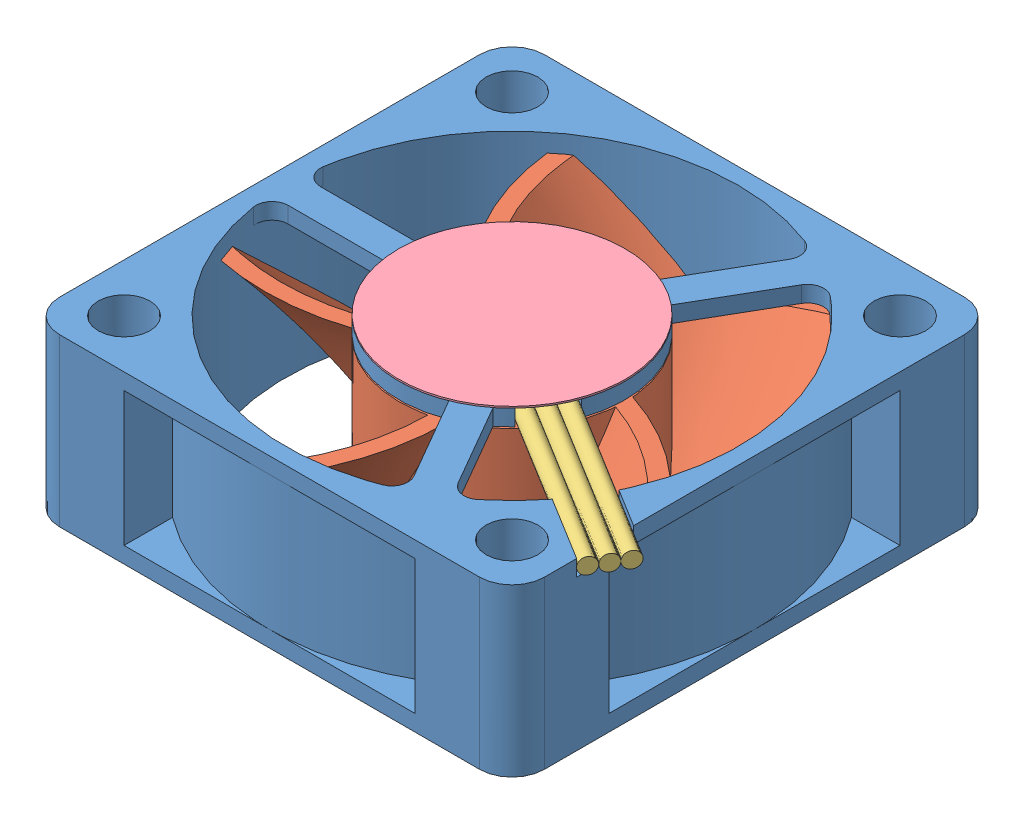
SolidWorks assembly 30mm_fan, configuration Predeterminado. Lengths in mm.
Overall size (39.9 10.46 39.91).
4 component instances, 4 part files, 11 mates.
Components (placement in the parent):
- 30mm_fan_frame-1: 30mm_fan_frame [Predeterminado] at (-11.6994 23.4046 0) size (30 10.3 30)
- 30mm_fanprop-1: 30mm_fanprop [Predeterminado] at (-11.6994 23.3046 0) x (-0.696705 0 0.717358) z (0 -1 0) size (28.39 28.05 9.26)
- Pieza2^30mm_fan-1: Pieza2^30mm_fan [Predeterminado] at (-11.6994 23.4046 0) x (0.524409 0 -0.851467) z (0.851467 0 0.524409) size (3 1 18.5) (virtual)
- Pieza3^30mm_fan-1: Pieza3^30mm_fan [Predeterminado] at (-11.6994 24.4046 0) x (1 0 0) z (0 1 0) size (14 14 0.1) (virtual)
Mates (geometry in assembly coordinates):
- Concéntrica1: concentric: cylinder of 30mm_fan_frame-1 through (-11.6994 22.4046 0) axis (0 1 0) radius 6; cylinder of 30mm_fanprop-1 through (-11.6994 14.1046 0) axis (0 1 0) radius 6
- Coincidente1: coincident: plane of 30mm_fan_frame-1 through (-11.6994 14.1046 0) normal (0 -1 0); plane of 30mm_fanprop-1 through (-11.6994 14.1046 0) normal (0 -1 0)
- EnPosición1: in place: plane of 30mm_fan_frame-1 through (-12.486 23.4046 1.2772) normal (0.851467 0 0.524409); plane of ? through (-8.482 0 -5.224) normal (0.851467 0 0.524409); moOrthogonalPlaneRef_w of 30mm_fan_frame-1 through (-12.486 23.4046 1.2772) normal (0.851467 0 0.524409); unknown of ?; plane of 30mm_fan_frame-1 through (-12.486 23.4046 1.2772) normal (0.851467 0 0.524409); plane of ? through (-8.482 0 -5.224) normal (0.524409 0 -0.851467); plane of 30mm_fan_frame-1 through (-12.486 23.4046 1.2772) normal (0.851467 0 0.524409); unknown of Pieza2^30mm_fan-1
- Coincidente2: coincident: plane of 30mm_fan_frame-1; plane of Pieza2^30mm_fan-1
- Coincidente3: coincident: moOrthogonalPlaneRef_w of 30mm_fan_frame-1 through (-11.6994 23.4046 0) normal (0 1 0); plane of Pieza2^30mm_fan-1
- Coincidente4: coincident: moOrthogonalPlaneRef_w of 30mm_fan_frame-1 through (-11.6994 23.4046 0) normal (-0.524409 0 0.851467); plane of Pieza2^30mm_fan-1 through (-11.6994 23.4046 0) normal (0.524409 0 -0.851467)
- EnPosición2: in place: plane of 30mm_fan_frame-1 through (-11.6994 24.4046 0) normal (0 1 0); plane of ? through (0 24.4046 0) normal (0 1 0); plane of 30mm_fan_frame-1 through (-11.6994 24.4046 0) normal (0 1 0); plane of ? through (0 24.4046 0) normal (0 0 -1); plane of 30mm_fan_frame-1 through (-11.6994 24.4046 0) normal (0 1 0); line of ? through (-55 0 24.4046) axis (0 1 0); plane of 30mm_fan_frame-1 through (-11.6994 24.4046 0) normal (0 1 0); unknown of Pieza3^30mm_fan-1
- Coincidente5: coincident: plane of 30mm_fan_frame-1; plane of Pieza3^30mm_fan-1
- Coincidente6: coincident: moOrthogonalPlaneRef_w of 30mm_fan_frame-1 through (-11.6994 24.4046 0) normal (0 0 -1); plane of Pieza3^30mm_fan-1 through (-11.6994 24.4046 0) normal (0 0 -1)
- Coincidente7: coincident: moOrthogonalPlaneRef_w of 30mm_fan_frame-1 through (-11.6994 24.4046 0) normal (-1 0 0); plane of Pieza3^30mm_fan-1
- Relación de posición de engranaje3: gear = 14 : 14 mm: cylinder of 30mm_fan_frame-1 through (-11.6994 23.4046 0) axis (0 1 0) radius 7; cylinder of 30mm_fanprop-1 through (-11.6994 14.1046 0) axis (0 1 0) radius 7
